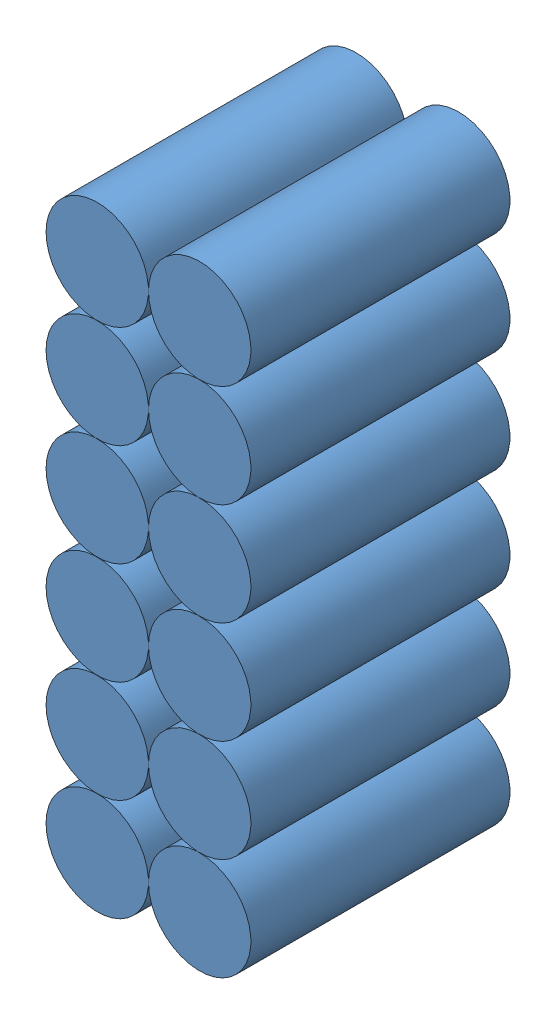
SolidWorks assembly Battery-Pack2x6, configuration Défaut. Lengths in mm.
Overall size (34 102 43).
12 component instances, 1 part files, 0 mates.
Components (placement in the parent):
- Batterie-Element-1: Batterie-Element [Défaut] at (5.6828 -14.1168 21.5) size (17 17 43)
- Batterie-Element-2: Batterie-Element [Défaut] at (-11.3172 -14.1168 21.5) size (17 17 43)
- Batterie-Element-3: Batterie-Element [Défaut] at (5.6828 2.8832 21.5) size (17 17 43)
- Batterie-Element-4: Batterie-Element [Défaut] at (5.6828 19.8832 21.5) size (17 17 43)
- Batterie-Element-5: Batterie-Element [Défaut] at (5.6828 36.8832 21.5) size (17 17 43)
- Batterie-Element-6: Batterie-Element [Défaut] at (5.6828 53.8832 21.5) size (17 17 43)
- Batterie-Element-7: Batterie-Element [Défaut] at (5.6828 70.8832 21.5) size (17 17 43)
- Batterie-Element-8: Batterie-Element [Défaut] at (-11.3172 2.8832 21.5) size (17 17 43)
- Batterie-Element-9: Batterie-Element [Défaut] at (-11.3172 19.8832 21.5) size (17 17 43)
- Batterie-Element-10: Batterie-Element [Défaut] at (-11.3172 36.8832 21.5) size (17 17 43)
- Batterie-Element-11: Batterie-Element [Défaut] at (-11.3172 53.8832 21.5) size (17 17 43)
- Batterie-Element-12: Batterie-Element [Défaut] at (-11.3172 70.8832 21.5) size (17 17 43)
